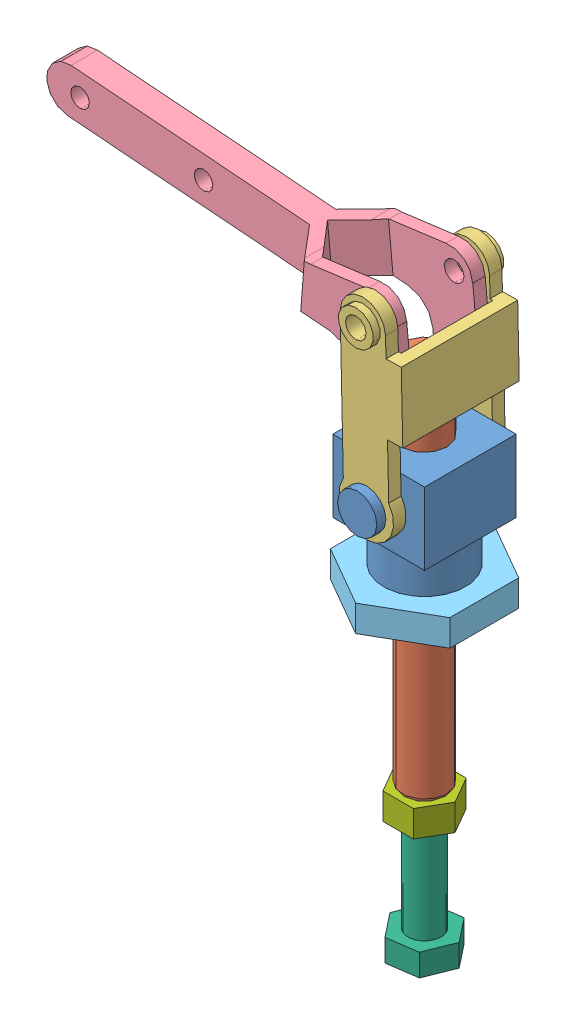
SolidWorks assembly Toggle Clamp (GH-36204-M), configuration Default. Lengths in mm.
Overall size (110.22 150.43 41.71).
7 component instances, 7 part files, 20 mates.
Components (placement in the parent):
- GH-36204-M PART 1-1: GH-36204-M PART 1 [Default] x (1 0 0) z (0 1 0) size (22.2 32.6 33.5)
- GH-36204-M PART 3-1: GH-36204-M PART 3 [Default] at (0 -49.741 0) x (1 0 0) z (0 1 0) size (10.88 10.88 90)
- GH-36204-M PART 5-1: GH-36204-M PART 5 [Default] at (0.8887 18.9241 0) x (0.999757 0.022039 0) z (-0.022039 0.999757 0) size (15.8 31.6 50.5)
- GH-36204-M PART 2-1: GH-36204-M PART 2 [Default] at (-41.4141 30.0458 0) x (-0.999061 -0.043334 0) z (0 0 -1) size (92.79 36.5 22)
- GH-36204-M PART 4-1: GH-36204-M PART 4 [Default] at (0 -21.5 0) x (0.866025 0 0.5) z (0 1 0) size (33.37 28.9 6.4)
- GH-36204-M PART 6-1: GH-36204-M PART 6 [Default] at (0 -44.741 0) x (0.619313 0 0.785144) z (0 -1 0) size (14.78 12.8 55.4)
- GH-36204-M PART 7-1: GH-36204-M PART 7 [Default] at (0 -64.741 0) x (1 0 0) z (0 -1 0) size (14.78 12.8 6.4)
Mates (geometry in assembly coordinates):
- Coincident1: coincident aligned: plane of GH-36204-M PART 1-1 through (0 0 0) normal (0 1 0); plane of assembly through (0 0 0) normal (0 1 0)
- Coincident2: coincident anti-aligned: plane of GH-36204-M PART 1-1 through (0 0 0) normal (0 0 -1); plane of assembly through (0 0 0) normal (0 0 1)
- Coincident3: coincident aligned: plane of GH-36204-M PART 1-1; plane of assembly through (0 0 0) normal (1 0 0)
- Concentric1: concentric anti-aligned: cylinder of GH-36204-M PART 3-1 through (0 -64.741 0) axis (0 1 0) radius 5.4; cylinder of GH-36204-M PART 1-1 through (0 -8.75 0) axis (0 -1 0) radius 9.9
- Parallel2: parallel anti-aligned: plane of GH-36204-M PART 1-1 through (11.1 -8.75 11.1) normal (0 0 1); plane of GH-36204-M PART 3-1 through (0 -49.741 0) normal (0 0 -1)
- Concentric7: concentric anti-aligned: cylinder of GH-36204-M PART 5-1 through (0 0.25 14.1) axis (0 0 -1) radius 2.5; cylinder of GH-36204-M PART 1-1 through (0 0.25 11.1) axis (0 0 1) radius 4.75
- Width3: width aligned: plane of GH-36204-M PART 5-1 through (0.5349 19.1028 14.1) normal (0 0 1); plane of GH-36204-M PART 5-1 through (0.5349 19.1028 -14.1) normal (0 0 -1); plane of GH-36204-M PART 1-1 through (11.1 -8.75 11.1) normal (0 0 1); plane of GH-36204-M PART 1-1 through (-11.1 -8.75 -11.1) normal (0 0 -1)
- Concentric8: concentric aligned: cylinder of GH-36204-M PART 3-1 through (0 19.0801 5.9) axis (0 0 -1) radius 2.5; cylinder of GH-36204-M PART 2-1 through (0 19.0801 11) axis (0 0 -1) radius 2.5
- Concentric9: concentric aligned: cylinder of GH-36204-M PART 5-1 through (-0.8441 38.5407 15.8) axis (0 0 -1) radius 2.5; cylinder of GH-36204-M PART 2-1 through (-0.8441 38.5407 11) axis (0 0 -1) radius 2.4
- Width4: width anti-aligned: plane of GH-36204-M PART 2-1 through (-36.2834 35.5082 -11) normal (0 0 -1); plane of GH-36204-M PART 2-1 through (-36.2834 35.5082 11) normal (0 0 1); plane of GH-36204-M PART 5-1 through (0.5349 19.1028 -14.1) normal (0 0 -1); plane of GH-36204-M PART 5-1 through (0.5349 19.1028 14.1) normal (0 0 1)
- Distance2: distance = 40 mm aligned: plane of GH-36204-M PART 1-1 through (0 -24.75 0) normal (0 -1 0); plane of GH-36204-M PART 3-1 through (0 -64.75 0) normal (0 -1 0)
- Distance3: distance = 2 mm aligned: plane of GH-36204-M PART 1-1 through (0 -24.75 0) normal (0 -1 0); plane of GH-36204-M PART 3-1 through (0 -26.75 0) normal (0 -1 0)
- LimitDistance2: limit distance = 39.991 mm aligned: plane of GH-36204-M PART 1-1 through (0 -24.75 0) normal (0 -1 0); plane of GH-36204-M PART 3-1 through (0 -64.741 0) normal (0 -1 0)
- Concentric10: concentric anti-aligned: cylinder of GH-36204-M PART 1-1 through (0 -8.75 0) axis (0 -1 0) radius 9.9; cylinder of GH-36204-M PART 4-1 through (0 -24.75 0) axis (0 1 0) radius 9.25
- Coincident4: coincident aligned: plane of GH-36204-M PART 1-1 through (0 -24.75 0) normal (0 -1 0); plane of GH-36204-M PART 4-1 through (0 -24.75 0) normal (0 -1 0)
- Parallel3: parallel aligned: plane of GH-36204-M PART 1-1 through (11.1 -8.75 -11.1) normal (1 0 0); plane of GH-36204-M PART 4-1 through (14.4503 -24.75 -8.3429) normal (1 0 0)
- Concentric11: concentric aligned: cylinder of GH-36204-M PART 3-1 through (0 -54.741 0) axis (0 1 0) radius 3.456; cylinder of GH-36204-M PART 6-1 through (0 -94.741 0) axis (0 1 0) radius 4
- Distance4: distance = 30 mm anti-aligned: plane of GH-36204-M PART 6-1 through (4.5768 -94.741 5.8023) normal (0 1 0); plane of GH-36204-M PART 3-1 through (0 -64.741 0) normal (0 -1 0)
- Concentric12: concentric anti-aligned: cylinder of GH-36204-M PART 6-1 through (0 -94.741 0) axis (0 1 0) radius 4; cylinder of GH-36204-M PART 7-1 through (0 -71.141 0) axis (0 -1 0) radius 3.5
- Coincident6: coincident anti-aligned: plane of GH-36204-M PART 3-1 through (0 -64.741 0) normal (0 -1 0); plane of GH-36204-M PART 7-1 through (7.3901 -64.741 0) normal (0 1 0)
